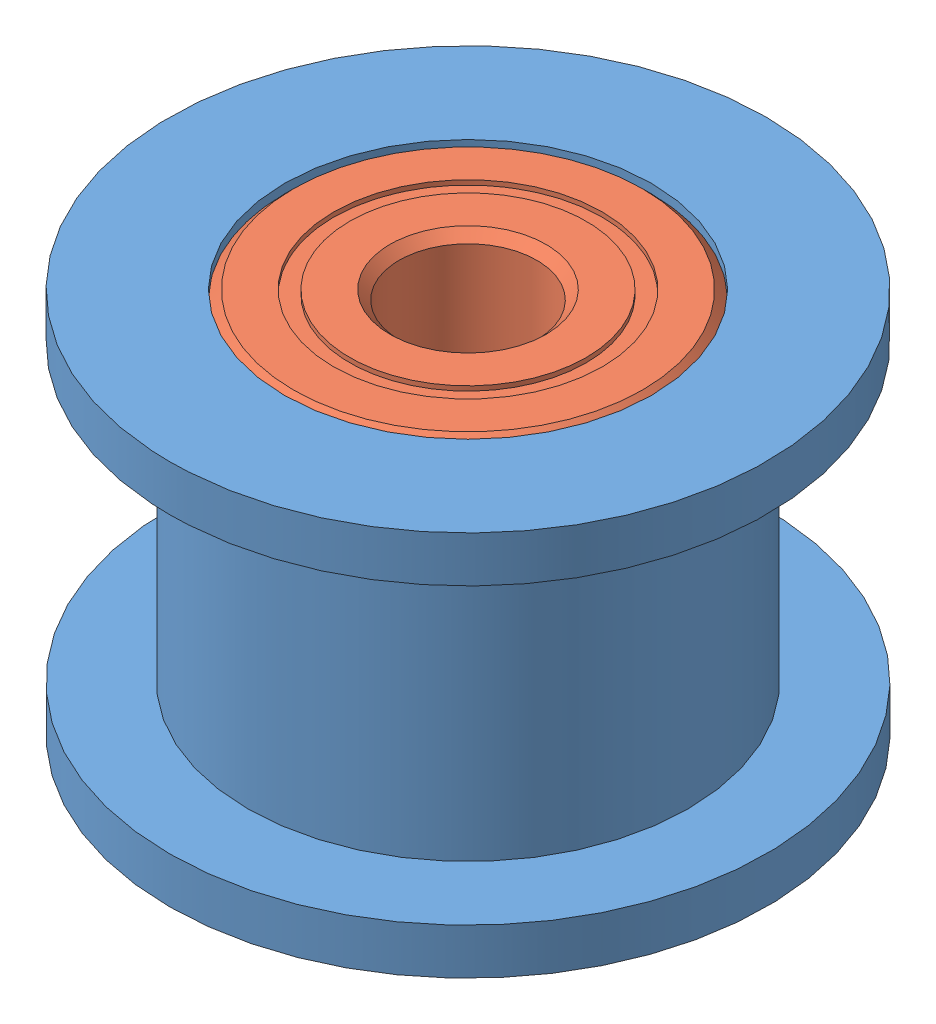
SolidWorks assembly 16T W6 B3 Without T, configuration Default. Lengths in mm.
Overall size (13 8.4 13.45).
3 component instances, 2 part files, 6 mates.
Components (placement in the parent):
- 16T W6 B3 Without T, Idler Pulley-1: 16T W6 B3 Without T, Idler Pulley [Default] at origin size (13 8.4 13)
- 16T W6 B3 Without T, 693-2Z BEARING, 8 mm OD, 3 mm ID, 4 mm WIDTH-1: 16T W6 B3 Without T, 693-2Z BEARING, 8 mm OD, 3 mm ID, 4 mm WIDTH [DEFAULT] at (0 2.2 0) x (-1 0 0) z (0 -1 0) size (8 10.95 4)
- 16T W6 B3 Without T, 693-2Z BEARING, 8 mm OD, 3 mm ID, 4 mm WIDTH-3: 16T W6 B3 Without T, 693-2Z BEARING, 8 mm OD, 3 mm ID, 4 mm WIDTH [DEFAULT] at (0 -2.2 0) x (1 0 0) z (0 1 0) size (8 10.95 4)
Mates (geometry in assembly coordinates):
- Coincident1: coordinate: point of assembly; point of 16T W6 B3 Without T, Idler Pulley-1; point of assembly
- Concentric1: concentric: cylinder of assembly; cylinder of assembly; cylinder of 16T W6 B3 Without T, Idler Pulley-1 through (0 -4.2 0) axis (0 1 0) radius 2; cylinder of 16T W6 B3 Without T, 693-2Z BEARING, 8 mm OD, 3 mm ID, 4 mm WIDTH-1 through (0 0.2 0) axis (0 -1 0) radius 1.5
- Coincident2: coincident: plane of assembly; plane of assembly; plane of 16T W6 B3 Without T, Idler Pulley-1 through (0 0.2 0) normal (0 1 0); plane of 16T W6 B3 Without T, 693-2Z BEARING, 8 mm OD, 3 mm ID, 4 mm WIDTH-1 through (0 0.2 -3.8) normal (0 -1 0)
- Concentric2: concentric: cylinder of 16T W6 B3 Without T, Idler Pulley-1 through (0 -4.2 0) axis (0 1 0) radius 2; cylinder of ? through (0 -4.2 0) axis (0 -1 0) radius 1.5
- Coincident3: coincident: plane of 16T W6 B3 Without T, Idler Pulley-1 through (0 -0.2 0) normal (0 -1 0); plane of ? through (0.5584 -0.2 3.7587) normal (0 1 0)
- Coincident4: coincident: plane of assembly through (0 0 0) normal (1 0 0); plane of 16T W6 B3 Without T, 693-2Z BEARING, 8 mm OD, 3 mm ID, 4 mm WIDTH-1 through (0 2.2 0) normal (-1 0 0); plane of assembly
